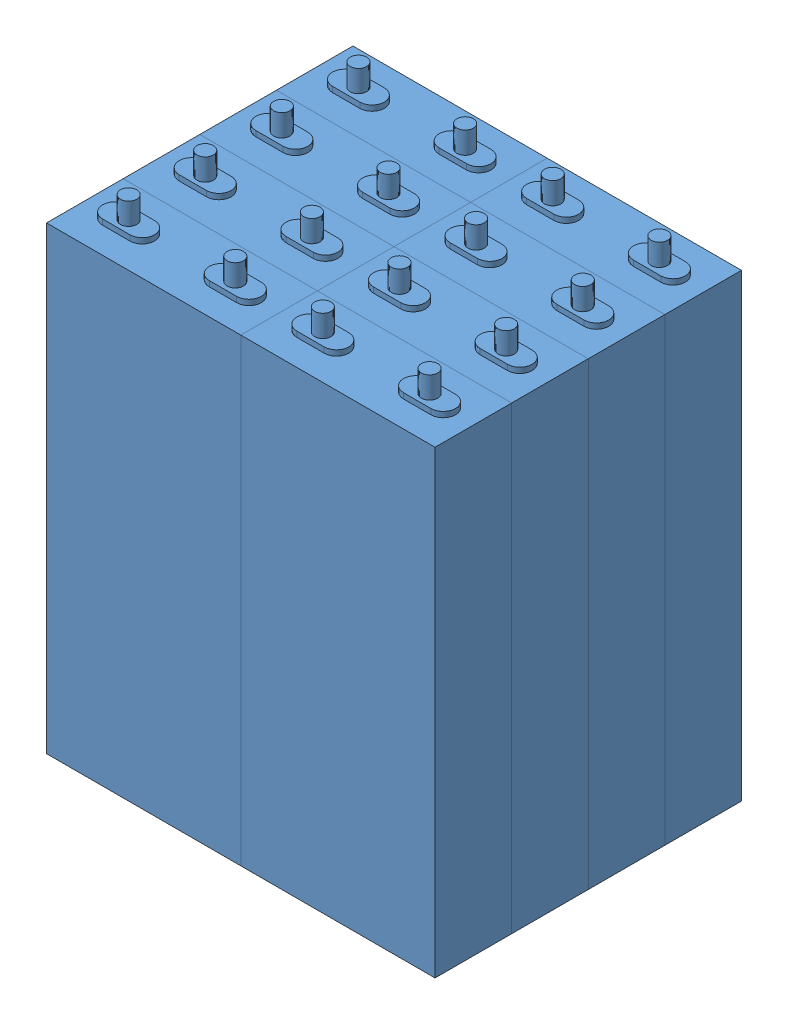
SolidWorks assembly Assemblage1, configuration Défaut. Lengths in mm.
Overall size (142 178 112).
8 component instances, 1 part files, 0 mates.
Components (placement in the parent):
- Cell_ZG_LFP020AH-1: Cell_ZG_LFP020AH [Défaut] at (-85.7799 -76.1802 0) size (71 178 28)
- Cell_ZG_LFP020AH-2: Cell_ZG_LFP020AH [Défaut] at (-85.7799 -76.1802 28) size (71 178 28)
- Cell_ZG_LFP020AH-3: Cell_ZG_LFP020AH [Défaut] at (-85.7799 -76.1802 56) size (71 178 28)
- Cell_ZG_LFP020AH-4: Cell_ZG_LFP020AH [Défaut] at (-85.7799 -76.1802 84) size (71 178 28)
- Cell_ZG_LFP020AH-5: Cell_ZG_LFP020AH [Défaut] at (-14.7799 -76.1802 0) size (71 178 28)
- Cell_ZG_LFP020AH-6: Cell_ZG_LFP020AH [Défaut] at (-14.7799 -76.1802 28) size (71 178 28)
- Cell_ZG_LFP020AH-7: Cell_ZG_LFP020AH [Défaut] at (-14.7799 -76.1802 56) size (71 178 28)
- Cell_ZG_LFP020AH-8: Cell_ZG_LFP020AH [Défaut] at (-14.7799 -76.1802 84) size (71 178 28)
